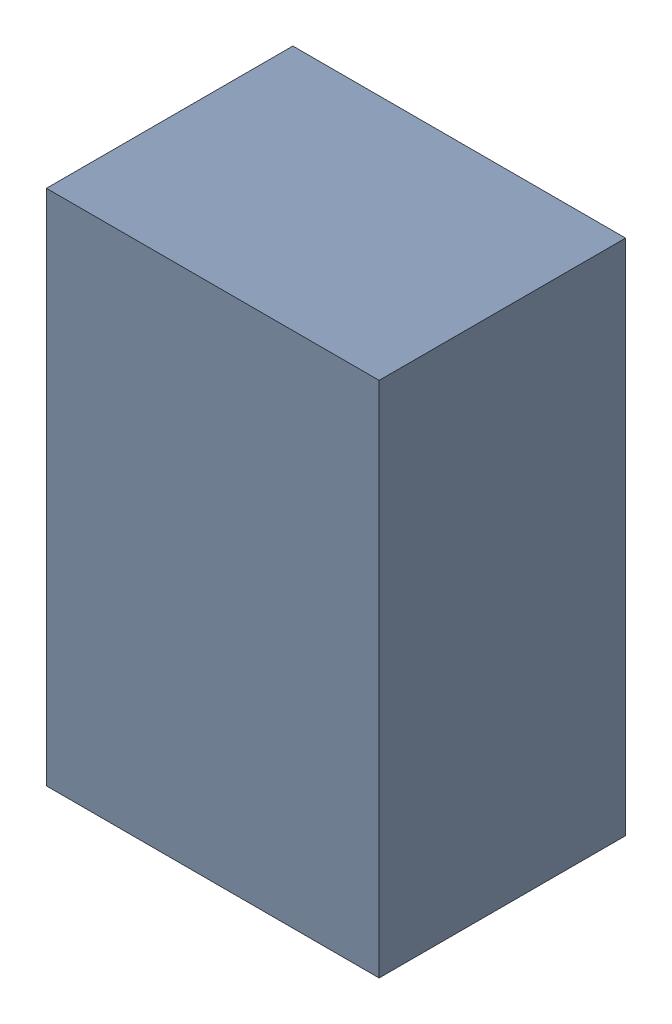
SolidWorks assembly U14, configuration ﾃﾞﾌｫﾙﾄ. Lengths in mm.
Overall size (1.35 2.1 1).
2 component instances, 1 part files, 0 mates.
Components (placement in the parent):
- 689262600-1: 689262600 [ﾃﾞﾌｫﾙﾄ] at (39.25 51.75 0) size (1.35 2.1 1)
  - Extruded_41-1: Extruded_41 [ﾃﾞﾌｫﾙﾄ] at origin size (1.35 2.1 1)
